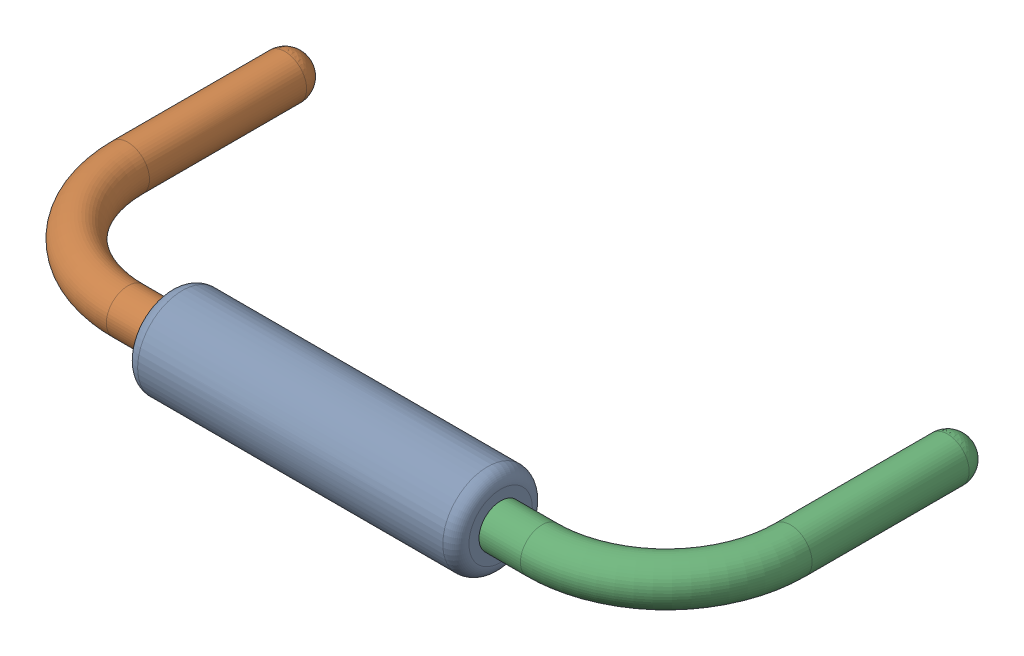
SolidWorks assembly R12, configuration Défaut. Lengths in mm.
Overall size (10.82 1.37 5.33).
4 component instances, 3 part files, 0 mates.
Components (placement in the parent):
- Open CASCADE STEP translator 6.8 1.10.1-1: Open CASCADE STEP translator 6.8 1.10.1 [Défaut] at origin size (10.82 1.37 5.33)
  - Body_1_7-1: Body_1_7 [Défaut] at origin size (5.08 1.37 1.37)
  - Pin_1_4-1: Pin_1_4 [Défaut] at origin size (3.2 0.66 4.98)
  - Pin_2_4-1: Pin_2_4 [Défaut] at (20.32 0 0) x (-1 0 0) z (0 0 1) size (3.2 0.66 4.98)
